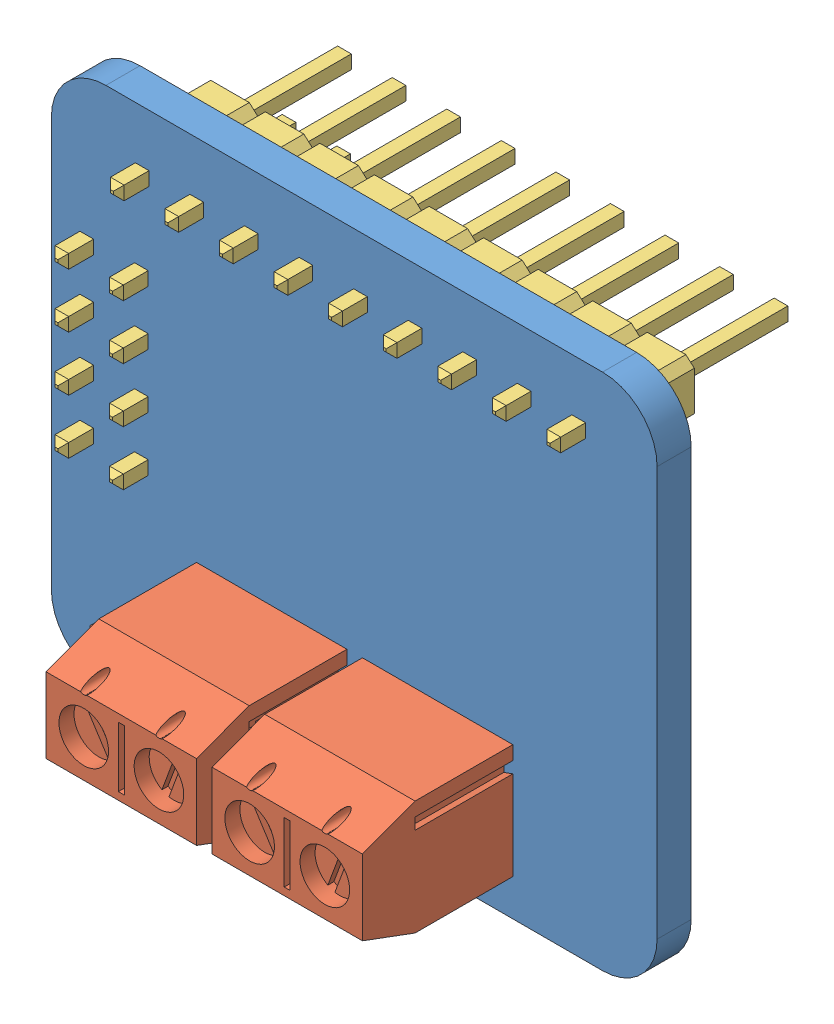
SolidWorks assembly ARDUINO AUDIO AMP MAX98306 987, configuration Default. Lengths in mm.
Overall size (28.19 24.13 16.66).
7 component instances, 3 part files, 10 mates.
Components (placement in the parent):
- ARDUINO AUDIO AMP MAX98306-1: ARDUINO AUDIO AMP MAX98306 [Default] at origin size (28.19 24.13 1.59)
- .100 Header-1: .100 Header [9] at (10.4511 9.3113 1.5875) x (0 -1 0) z (0 0 1) size (2.54 22.86 11.07) (hidden)
- .100 Header-2: .100 Header [2x4] at (-12.4471 5.2634 1.5875) size (5.08 10.16 11.07) (hidden)
- Jack-1: Jack [Default] at (-3.839 -7.7152 1.5875) x (1 0 0) z (0 -1 0) size (7.42 9.1 5.32)
- Jack-2: Jack [Default] at (3.8828 -7.6995 1.5875) x (1 0 0) z (0 -1 0) size (7.42 9.1 5.32)
- .100 Header-3: .100 Header [9] at (10.4511 9.3113 0) x (0 1 0) z (0 0 -1) size (2.54 22.86 11.07)
- .100 Header-4: .100 Header [2x4] at (-9.9071 5.2634 0) x (-1 0 0) z (0 0 -1) size (5.08 10.16 11.07)
Mates (geometry in assembly coordinates):
- Coincident1: coincident anti-aligned: plane of ARDUINO AUDIO AMP MAX98306-1 through (-11.557 -9.525 1.5875) normal (0 0 1); plane of .100 Header-1 through (10.4511 9.3113 1.5875) normal (0 0 -1)
- Coincident2: coincident anti-aligned: plane of ARDUINO AUDIO AMP MAX98306-1 through (-11.557 -9.525 1.5875) normal (0 0 1); plane of .100 Header-2 through (-12.4471 5.2634 1.5875) normal (0 0 -1)
- Coincident31: coincident anti-aligned: plane of ARDUINO AUDIO AMP MAX98306-1 through (-11.557 -9.525 1.5875) normal (0 0 1); plane of Jack-1 through (-7.339 -5.0552 1.5875) normal (0 0 -1)
- Coincident41: coincident anti-aligned: plane of ARDUINO AUDIO AMP MAX98306-1 through (-11.557 -9.525 1.5875) normal (0 0 1); plane of Jack-2 through (0.3828 -5.0395 1.5875) normal (0 0 -1)
- Coincident42: coincident aligned: plane of .100 Header-2 through (-13.7176 6.1598 4.1275) normal (-1 0 0); plane of .100 Header-4 through (-13.7176 6.1198 -2.54) normal (-1 0 0)
- Coincident43: coincident aligned: plane of .100 Header-2 through (-8.9902 -3.6466 4.1275) normal (0 -1 0); plane of .100 Header-4 through (-10.8241 -3.6466 -2.54) normal (0 -1 0)
- Coincident44: coincident anti-aligned: plane of ARDUINO AUDIO AMP MAX98306-1 through (-11.557 -9.525 0) normal (0 0 -1); plane of .100 Header-4 through (-9.9071 -2.3566 0) normal (0 0 1)
- Coincident45: coincident aligned: plane of .100 Header-1 through (-8.9725 10.5818 4.1275) normal (0 1 0); plane of .100 Header-3 through (-9.0125 10.5818 -2.54) normal (0 1 0)
- Coincident46: coincident aligned: plane of .100 Header-1 through (-11.1589 8.3944 4.1275) normal (-1 0 0); plane of .100 Header-3 through (-11.1589 10.2283 -2.54) normal (-1 0 0)
- Coincident47: coincident anti-aligned: plane of ARDUINO AUDIO AMP MAX98306-1 through (-11.557 -9.525 0) normal (0 0 -1); plane of .100 Header-3 through (-9.8689 9.3113 0) normal (0 0 1)
